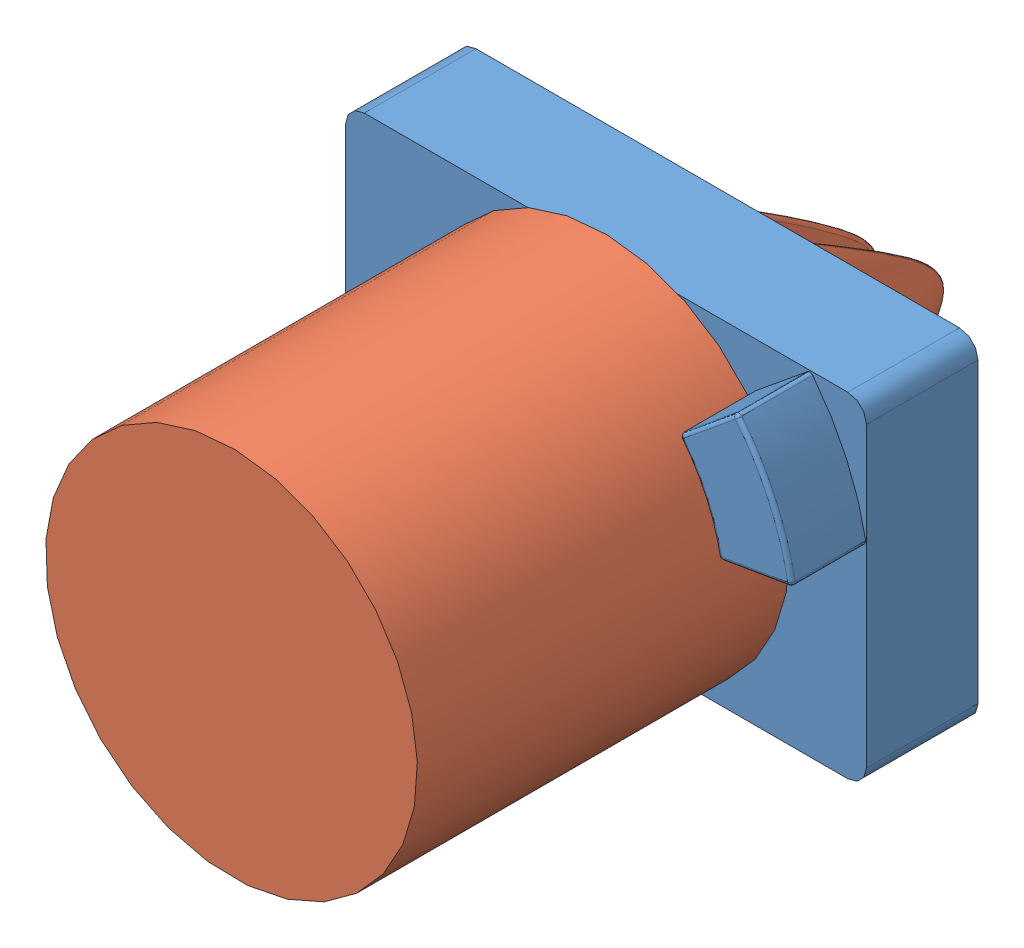
SolidWorks assembly snapper_v1, configuration Default. Lengths in mm.
Overall size (14 11.32 18.44).
2 component instances, 2 part files, 1 mates.
Components (placement in the parent):
- base-1: base [Default] at origin size (14 9 5)
- snapper-1: snapper [Default] at (0 0 3.0698) x (0 0 -1) z (0.989878 0.141922 0) size (18.44 10 10)
Mates (geometry in assembly coordinates):
- Concentric1: concentric aligned: cylinder of base-1 through (0 0 3) axis (0 0 -1) radius 2.5; cylinder of snapper-1 through (0 0 13.0698) axis (0 0 -1) radius 5
